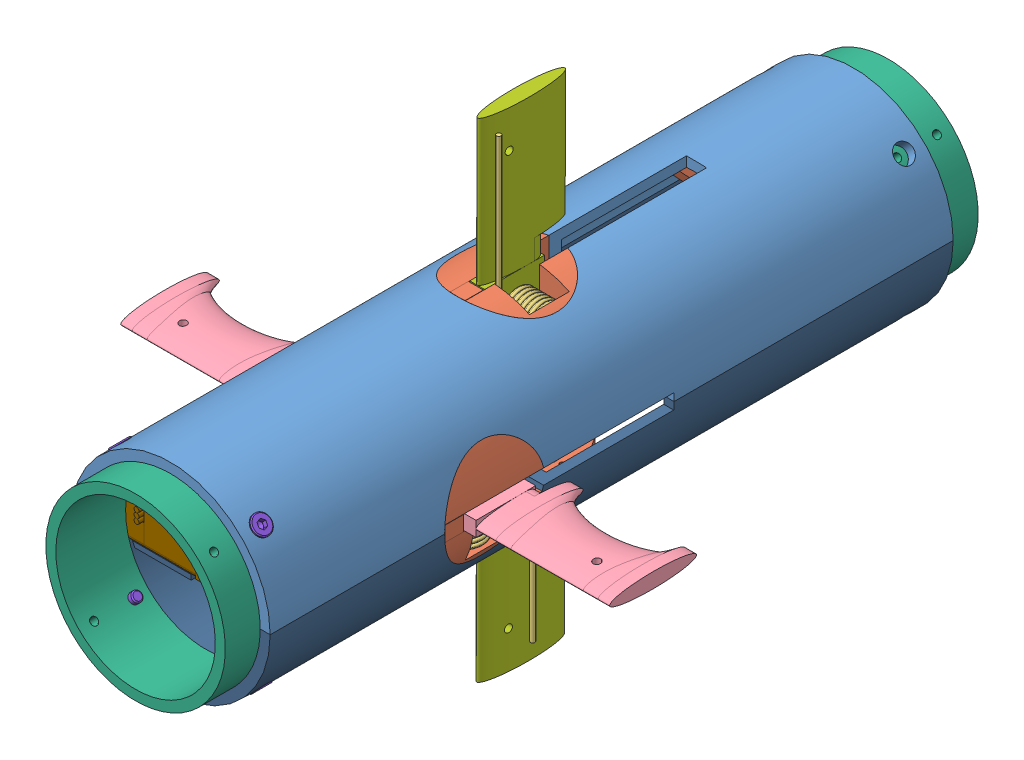
SolidWorks assembly Сборка Полного управления 3, configuration Default. Lengths in mm.
Overall size (97.92 97.94 151).
29 component instances, 12 part files, 37 mates.
Components (placement in the parent):
- Корпус Управления 3-1: Корпус Управления 3 [Default] at (1.7361 16.2761 25.79) size (40 20.98 137)
- Сборка управления 3-2: Сборка управления 3 [Default] at (-21.3568 27.5358 32.1537) x (0 -1 -0.000577) z (0 -0.000577 1) size (25 97.92 24.75)
  - Ось Рулей 2-1: Ось Рулей 2 [Default] at (11.2417 23.0929 31.1428) size (25 40 24.75)
  - Пружина 1-1: Пружина 1 [Default] at (16.1032 37.0366 31.1428) x (1 0 0) z (0 -1 0) size (7.17 7.86 53.5)
  - Пружина 1-2: Пружина 1 [Default] at (16.1032 9.1492 31.1428) x (1 0 0) z (0 1 0) size (7.17 7.86 53.5)
  - Плоскость 3-1: Плоскость 3 [Default] at (12.7417 37.0366 31.1428) x (0 0.003497 0.999994) z (-1 0 0) size (17.55 41 3.05)
  - Плоскость 3-2: Плоскость 3 [Default] at (9.7417 9.1492 31.1428) x (0 0.001392 0.999999) z (1 0 0) size (17.55 41 3.05)
  - ЗАТЫЧКА-1: ЗАТЫЧКА [Default] at (7.7417 37.0366 31.1428) x (0 0.246907 -0.969039) z (1 0 0) size (5 5 13)
  - ЗАТЫЧКА-2: ЗАТЫЧКА [Default] at (7.7417 9.1492 31.1428) x (0 0.246907 -0.969039) z (1 0 0) size (5 5 13)
- Кольцо-1: Кольцо [Default] at (1.7361 16.2761 101.29) x (0.707107 -0.707107 0) z (0 0 1) size (36 36 14)
- Кольцо-3: Кольцо [Default] at (1.7361 16.2761 -35.71) x (-0.707107 -0.707107 0) z (0 0 1) size (36 36 14)
- Сборка управления 3-1-1: Сборка управления 3-1 [Default] at (-9.5056 -6.8168 9.6472) size (25 97.94 24.75)
  - Ось Рулей 2-1: Ось Рулей 2 [Default] at (11.2417 23.0929 31.1428) size (25 40 24.75)
  - Пружина 1-1: Пружина 1 [Default] at (16.1032 37.0366 31.1428) x (1 0 0) z (0 -1 0) size (7.17 7.86 53.5)
  - Пружина 1-2: Пружина 1 [Default] at (16.1032 9.1492 31.1428) x (1 0 0) z (0 1 0) size (7.17 7.86 53.5)
  - ЗАТЫЧКА-1: ЗАТЫЧКА [Default] at (7.7417 37.0366 31.1428) x (0 0.246907 -0.969039) z (1 0 0) size (5 5 13)
  - ЗАТЫЧКА-2: ЗАТЫЧКА [Default] at (7.7417 9.1492 31.1428) x (0 0.246907 -0.969039) z (1 0 0) size (5 5 13)
  - Плоскость 3-1-1: Плоскость 3-1 [Default] at (12.7417 37.0366 31.1428) x (0 0.003248 0.999995) z (-1 0 0) size (17.5 41 4)
  - Плоскость 3-1-2: Плоскость 3-1 [Default] at (9.7417 9.1492 31.1428) x (0 0.002592 0.999997) z (1 0 0) size (17.5 41 4)
- socket head cap screw_am-2: socket head cap screw_am [B18.3.1M - 2 x 0.4 x 4 Hex SHCS -- 4NHX] at (-13.0672 1.4728 104.29) x (0.707107 0.707107 0) z (-0.316994 0.316994 0.893884) size (6 3.8 3.8)
- socket head cap screw_am-4: socket head cap screw_am [B18.3.1M - 2 x 0.4 x 4 Hex SHCS -- 4NHX] at (15.9679 2.0443 104.29) x (-0.707107 0.707107 0) z (0.298832 0.298832 0.906311) size (6 3.8 3.8)
- socket head cap screw_am-5: socket head cap screw_am [B18.3.1M - 2 x 0.4 x 4 Hex SHCS -- 4NHX] at (16.1774 30.7174 104.29) x (-0.707107 -0.707107 0) z (0.512143 -0.512143 0.689507) size (6 3.8 3.8)
- socket head cap screw_am-6: socket head cap screw_am [B18.3.1M - 2 x 0.4 x 4 Hex SHCS -- 4NHX] at (-12.5506 30.5628 104.29) x (0.707107 -0.707107 0) z (-0.614974 -0.614974 0.493572) size (6 3.8 3.8)
- SG90 1.2kgm Servo-5: SG90 1.2kgm Servo [Peça] at (1.7361 7.8261 -9.21) x (0 0 -1) z (1 0 0) size (23.5 29.95 12.4)
- SG90 1.2kgm Servo-6: SG90 1.2kgm Servo [Peça] at (-6.7139 16.2761 88.75) x (0 0 -1) z (0 -1 0) size (23.5 29.95 12.4)
- Корпус Управления 3.1-1: Корпус Управления 3.1 [Default] at (1.7361 16.2761 25.79) size (40 20.98 137)
- SG90 - Micro Servo 9g - Tower Pro.3-1: SG90 - Micro Servo 9g - Tower Pro.3 [Peça] at (13.2861 16.2761 93.9) x (0 -0.689553 0.724235) z (0 0.724235 0.689553) size (22.9 3.8 6.9)
- SG90 - Micro Servo 9g - Tower Pro.3-2: SG90 - Micro Servo 9g - Tower Pro.3 [Peça] at (1.7361 27.8261 -4.06) x (-1 0 0.0002) z (-0.0002 0 -1) size (22.9 3.8 6.9)
- Тяга 1-2: Тяга 1 [Default] at (12.1861 19.8261 -4.0621) x (0.999841 0 -0.017834) z (0.017834 0 0.999841) size (1.2 9.6 46.06)
Mates (geometry in assembly coordinates):
- Concentric3: concentric anti-aligned: cylinder of Корпус Управления 3-1 through (1.7361 -3.7239 40.79) axis (0 1 0) radius 10; cylinder of Сборка управления 3-1/Ось Рулей 2-1 through (1.7361 36.2761 40.79) axis (0 -1 0) radius 10
- Tangent1: tangent aligned: cylinder of Корпус Управления 3-1 through (1.7361 16.2761 55.79) axis (0 0 -1) radius 20; cylinder of Сборка управления 3-1/Ось Рулей 2-1 through (1.6547 16.2761 20.7902) axis (0.00407 0 0.999992) radius 20
- Concentric4: concentric anti-aligned: cylinder of Корпус Управления 3-1 through (-20.7639 16.2761 63.29) axis (1 0 0) radius 10; cylinder of Сборка управления 3-2/Ось Рулей 2-1 through (21.7361 16.2761 63.29) axis (-1 0 0) radius 10
- Tangent2: tangent aligned: cylinder of Корпус Управления 3-1 through (1.7361 16.2761 55.79) axis (0 0 -1) radius 20; cylinder of Сборка управления 3-2/Ось Рулей 2-1 through (1.7361 16.2877 43.29) axis (0 -0.000577 1) radius 20
- Concentric5: concentric aligned: cylinder of Корпус Управления 3-1 through (1.7361 16.2761 55.79) axis (0 0 -1) radius 18; cylinder of Кольцо-1 through (1.7361 16.2761 115.29) axis (0 0 -1) radius 18
- Concentric11: concentric anti-aligned: cylinder of Корпус Управления 3-1 through (21.7371 36.2771 104.29) axis (-0.707107 -0.707107 0) radius 1.875; cylinder of Кольцо-1 through (10.9285 25.4685 104.29) axis (0.707107 0.707107 0) radius 0.75
- Concentric12: concentric aligned: cylinder of Корпус Управления 3-1 through (1.7361 16.2761 55.79) axis (0 0 -1) radius 18; cylinder of Кольцо-3 through (1.7361 16.2761 -21.71) axis (0 0 -1) radius 18
- Concentric13: concentric aligned: cylinder of Корпус Управления 3.1-1 through (21.7371 36.2771 -24.71) axis (-0.707107 -0.707107 0) radius 1.875; cylinder of Кольцо-3 through (-7.4563 7.0837 -24.71) axis (-0.707107 -0.707107 0) radius 0.75
- Concentric14: concentric aligned: cylinder of Кольцо-3 through (1.7361 16.2761 -21.71) axis (0 0 -1) radius 18; cylinder of Нос-1 through (1.7361 16.2761 -58.71) axis (0 0 -1) radius 18
- Concentric15: concentric aligned: cylinder of Кольцо-3 through (-7.4563 7.0837 -32.71) axis (-0.707107 -0.707107 0) radius 0.75; cylinder of Нос-1 through (15.8789 30.419 -32.71) axis (-0.707107 -0.707107 0) radius 1.875
- Concentric16: concentric anti-aligned: cylinder of Корпус Управления 3-1 through (1.7361 -3.7239 40.79) axis (0 1 0) radius 10; cylinder of Сборка управления 3-1-1/Ось Рулей 2-1 through (1.7361 36.2761 40.79) axis (0 -1 0) radius 10
- Tangent4: tangent aligned: cylinder of Корпус Управления 3-1 through (1.7361 16.2761 55.79) axis (0 0 -1) radius 20; cylinder of Сборка управления 3-1-1/Ось Рулей 2-1 through (1.7361 16.2761 20.79) axis (0 0 1) radius 20
- Concentric20: concentric aligned: cylinder of Кольцо-1 through (-7.4563 7.0837 104.29) axis (-0.707107 -0.707107 0) radius 0.75; cylinder of socket head cap screw_am-2 through (-35.5179 -20.9778 104.29) axis (-0.707107 -0.707107 0) radius 1.9
- Concentric22: concentric aligned: cylinder of Кольцо-1 through (-7.4563 25.4685 104.29) axis (-0.707107 0.707107 0) radius 0.75; cylinder of socket head cap screw_am-6 through (-35.0013 53.0135 104.29) axis (-0.707107 0.707107 0) radius 1
- Concentric23: concentric aligned: cylinder of Кольцо-1 through (10.9285 25.4685 104.29) axis (0.707107 0.707107 0) radius 0.75; cylinder of socket head cap screw_am-5 through (38.628 53.1681 104.29) axis (0.707107 0.707107 0) radius 1
- Concentric24: concentric aligned: cylinder of Кольцо-1 through (10.9285 7.0837 104.29) axis (0.707107 -0.707107 0) radius 0.75; cylinder of socket head cap screw_am-4 through (38.4185 -20.4063 104.29) axis (0.707107 -0.707107 0) radius 1
- Coincident2: coincident aligned: plane of Корпус Управления 3-1 through (1.7361 16.2761 25.79) normal (0 1 0); plane of SG90 1.2kgm Servo-1 through (26.1892 16.2761 82.69) normal (0 1 0)
- Coincident4: coincident anti-aligned: plane of SG90 1.2kgm Servo-2 through (-13.4375 15.6908 111.0186) normal (-0.002902 0.999944 0.010156); plane of SG90 1.2kgm Servo-3 through (16.9459 15.7892 110.0169) normal (0.002902 -0.999944 -0.010156)
- Coincident5: coincident aligned: plane of SG90 1.2kgm Servo-2 through (-8.0374 14.6734 129.0409) normal (0.03298 -0.010055 0.999405); plane of SG90 1.2kgm Servo-3 through (12.7463 16.4406 128.3729) normal (0.03298 -0.010055 0.999405)
- Coincident6: coincident aligned: plane of SG90 1.2kgm Servo-2 through (13.083 14.9013 112.6369) normal (0.999452 0.003236 -0.032949); plane of SG90 1.2kgm Servo-3 through (13.078 16.6012 112.6542) normal (0.999452 0.003236 -0.032949)
- Coincident8: coincident anti-aligned: plane of Корпус Управления 3-1 through (1.7361 16.2761 25.79) normal (0 1 0); plane of SG90 1.2kgm Servo-6 through (-6.7139 16.2761 88.75) normal (0 -1 0)
- Distance2: distance = 35 mm aligned: plane of Корпус Управления 3-1 through (1.7361 16.2761 25.79) normal (0 0 1); plane of SG90 1.2kgm Servo-5 through (1.7361 7.8261 -9.21) normal (0 0 1)
- Coincident12: coincident aligned: plane of Корпус Управления 3-1 through (1.7361 16.2761 25.79) normal (1 0 0); plane of SG90 1.2kgm Servo-5 through (1.7361 7.8261 -9.21) normal (1 0 0)
- Distance3: distance = 77.5 mm anti-aligned: plane of SG90 1.2kgm Servo-6 through (-1.5639 11.0261 77.5) normal (0 0 -1)
- Distance4: distance = 19 mm: plane of SG90 1.2kgm Servo-5 through (6.9861 -2.7239 1.19) normal (0 -1 0); cylinder of Корпус Управления 3-1 through (1.7361 16.2761 55.79) axis (0 0 -1) radius 20
- Distance5: distance = 19 mm: plane of SG90 1.2kgm Servo-6 through (-17.2639 11.0261 99.15) normal (-1 0 0); cylinder of Корпус Управления 3-1 through (1.7361 16.2761 55.79) axis (0 0 -1) radius 20
- Concentric25: concentric aligned: cylinder of Кольцо-3 through (1.7361 16.2761 -21.71) axis (0 0 -1) radius 18; cylinder of Корпус Управления 3.1-1 through (1.7361 16.2761 55.79) axis (0 0 -1) radius 18
- Concentric26: concentric aligned: cylinder of Кольцо-1 through (-7.4563 7.0837 104.29) axis (-0.707107 -0.707107 0) radius 0.75; cylinder of Корпус Управления 3.1-1 through (21.7371 36.2771 104.29) axis (-0.707107 -0.707107 0) radius 1.875
- Coincident13: coincident anti-aligned: plane of SG90 1.2kgm Servo-6 through (9.4861 16.2761 93.9) normal (1 0 0); plane of SG90 - Micro Servo 9g - Tower Pro.3-1 through (9.4861 16.2761 93.9) normal (-1 0 0)
- Concentric27: concentric aligned: circle of SG90 1.2kgm Servo-6; cylinder of SG90 - Micro Servo 9g - Tower Pro.3-1 through (13.2861 16.2761 93.9) axis (1 0 0) radius 1.05
- Coincident15: coincident aligned: plane of SG90 1.2kgm Servo-5 through (1.7361 24.0261 -4.06) normal (0 1 0); circle of SG90 - Micro Servo 9g - Tower Pro.3-2
- Concentric28: concentric anti-aligned: circle of SG90 1.2kgm Servo-5; circle of SG90 - Micro Servo 9g - Tower Pro.3-2
- Parallel1: parallel: plane of SG90 1.2kgm Servo-5 through (7.8361 15.4761 5.99) normal (1 0 0); plane of SG90 - Micro Servo 9g - Tower Pro.3-2
- Coincident18: coincident anti-aligned: circle of SG90 - Micro Servo 9g - Tower Pro.3-2; circle of Тяга 1-1
- Parallel4: parallel aligned: plane of Сборка управления 3-1-1/Ось Рулей 2-1 through (-0.7639 24.7761 40.79) normal (1 0 0); plane of SG90 1.2kgm Servo-6 through (5.1361 11.6761 84) normal (1 0 0)
- Coincident22: coincident anti-aligned: circle of SG90 - Micro Servo 9g - Tower Pro.3-2; circle of Тяга 1-2
- Concentric32: concentric anti-aligned: cylinder of Сборка управления 3-1-1/Ось Рулей 2-1 through (12.9861 -3.7239 40.79) axis (0 1 0) radius 0.6; cylinder of Тяга 1-2 through (12.9861 27.8261 40.79) axis (0 -1 0) radius 0.6
